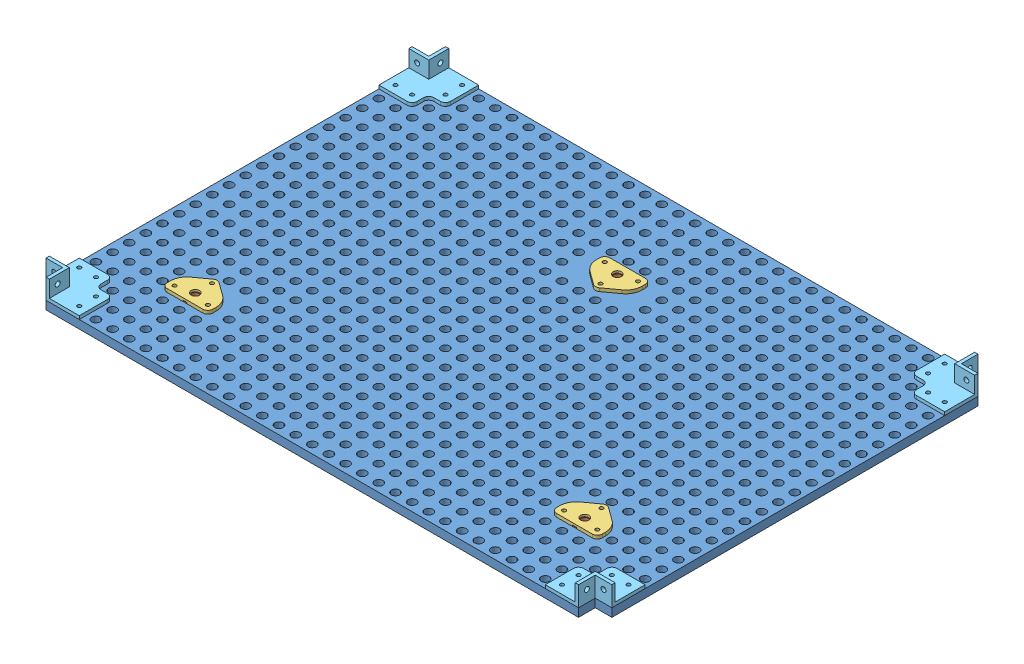
SolidWorks assembly PlateauZ, configuration Défaut. Lengths in mm.
Overall size (680 38 480).
14 component instances, 5 part files, 36 mates.
Components (placement in the parent):
- plaque_repartition_aire_chaud_300x544mm-1: plaque_repartition_aire_chaud_300x544mm [Défaut] at (-104.4522 80.5239 57) size (680 10 480)
- F608ZZ-2: F608ZZ [Défaut] at (-318.4522 85.0239 173.5) x (1 0 0) z (0 1 0) size (25 25 7)
- F608ZZ-3: F608ZZ [Défaut] at (149.5478 85.0239 173.5) x (1 0 0) z (0 1 0) size (25 25 7)
- F608ZZ-4: F608ZZ [Défaut] at (-84.4522 85.0239 -99.5) x (1 0 0) z (0 1 0) size (25 25 7)
- BloqueF608ZZHaut-1: BloqueF608ZZHaut [Défaut] at (122.0829 90.5239 145.9649) x (-0.999999 0 -0.001276) z (0 1 0) size (55 38.58 4)
- BloqueF608ZZHaut-2: BloqueF608ZZHaut [Défaut] at (-345.9522 90.5239 146) x (-1 0 0) z (0 1 0) size (55 38.58 4)
- BloqueF608ZZHaut-3: BloqueF608ZZHaut [Défaut] at (-56.9522 90.5239 -72) x (1 0 0) z (0 1 0) size (55 38.58 4)
- BloqueF608ZZBas-1: BloqueF608ZZBas [Défaut] at (177.0829 80.5239 146.0351) x (0.999999 0 0.001276) z (0 -1 0) size (55 38.58 8.5)
- BloqueF608ZZBas-2: BloqueF608ZZBas [Défaut] at (-290.9522 80.5239 146) x (1 0 0) z (0 -1 0) size (55 38.58 8.5)
- BloqueF608ZZBas-3: BloqueF608ZZBas [Défaut] at (-111.9522 80.5239 -72) x (-1 0 0) z (0 -1 0) size (55 38.58 8.5)
- FixationPlateauZ-1: FixationPlateauZ [Défaut] at (255.5478 90.5239 -193) x (0 0 -1) z (0 1 0) size (60 60 24)
- FixationPlateauZ-2: FixationPlateauZ [Défaut] at (235.5478 90.5239 267) x (1 0 0) z (0 1 0) size (60 60 24)
- FixationPlateauZ-3: FixationPlateauZ [Défaut] at (-424.4522 90.5239 247) x (0 0 1) z (0 1 0) size (60 60 24)
- FixationPlateauZ-4: FixationPlateauZ [Défaut] at (-404.4522 90.5239 -213) x (-1 0 0) z (0 1 0) size (60 60 24)
Mates (geometry in assembly coordinates):
- Coaxiale1: concentric aligned: cylinder of plaque_repartition_aire_chaud_300x544mm-1 through (-318.4522 90.5239 173.5) axis (0 -1 0) radius 11; cylinder of F608ZZ-2 through (-318.4522 90.5239 173.5) axis (0 -1 0) radius 11
- Coaxiale2: concentric aligned: cylinder of plaque_repartition_aire_chaud_300x544mm-1 through (149.5478 90.5239 173.5) axis (0 -1 0) radius 11; cylinder of F608ZZ-3 through (149.5478 90.5239 173.5) axis (0 -1 0) radius 11
- Coaxiale3: concentric aligned: cylinder of plaque_repartition_aire_chaud_300x544mm-1 through (-84.4522 90.5239 -99.5) axis (0 -1 0) radius 11; cylinder of F608ZZ-4 through (-84.4522 90.5239 -99.5) axis (0 -1 0) radius 11
- Coïncidente1: coincident anti-aligned: plane of plaque_repartition_aire_chaud_300x544mm-1 through (-104.4522 90.5239 57) normal (0 1 0); plane of F608ZZ-4 through (-84.4522 90.5239 -99.5) normal (0 -1 0)
- Coïncidente2: coincident anti-aligned: plane of plaque_repartition_aire_chaud_300x544mm-1 through (-104.4522 90.5239 57) normal (0 1 0); plane of F608ZZ-2 through (-318.4522 90.5239 173.5) normal (0 -1 0)
- Coïncidente3: coincident anti-aligned: plane of plaque_repartition_aire_chaud_300x544mm-1 through (-104.4522 90.5239 57) normal (0 1 0); plane of F608ZZ-3 through (149.5478 90.5239 173.5) normal (0 -1 0)
- Coïncidente4: coincident anti-aligned: plane of plaque_repartition_aire_chaud_300x544mm-1 through (-104.4522 90.5239 57) normal (0 1 0); plane of BloqueF608ZZHaut-1 through (122.0829 90.5239 145.9649) normal (0 -1 0)
- Coaxiale4: concentric aligned: cylinder of plaque_repartition_aire_chaud_300x544mm-1 through (149.5733 90.5239 153.5) axis (0 -1 0) radius 2.25; cylinder of BloqueF608ZZHaut-1 through (149.5733 94.5239 153.5) axis (0 -1 0) radius 2.25
- Coaxiale5: concentric aligned: cylinder of F608ZZ-3 through (149.5478 90.5239 173.5) axis (0 -1 0) radius 4; cylinder of BloqueF608ZZHaut-1 through (149.5478 94.5239 173.5) axis (0 -1 0) radius 5
- Coïncidente5: coincident anti-aligned: plane of plaque_repartition_aire_chaud_300x544mm-1 through (-104.4522 90.5239 57) normal (0 1 0); plane of BloqueF608ZZHaut-2 through (-345.9522 90.5239 146) normal (0 -1 0)
- Coaxiale6: concentric aligned: cylinder of F608ZZ-2 through (-318.4522 90.5239 173.5) axis (0 -1 0) radius 4; cylinder of BloqueF608ZZHaut-2 through (-318.4522 94.5239 173.5) axis (0 -1 0) radius 5
- Coaxiale7: concentric aligned: cylinder of plaque_repartition_aire_chaud_300x544mm-1 through (-318.4522 90.5239 153.5) axis (0 -1 0) radius 2.25; cylinder of BloqueF608ZZHaut-2 through (-318.4522 94.5239 153.5) axis (0 -1 0) radius 2.25
- Coïncidente6: coincident anti-aligned: plane of plaque_repartition_aire_chaud_300x544mm-1 through (-104.4522 90.5239 57) normal (0 1 0); plane of BloqueF608ZZHaut-3 through (-56.9522 90.5239 -72) normal (0 -1 0)
- Coaxiale8: concentric aligned: cylinder of F608ZZ-4 through (-84.4522 90.5239 -99.5) axis (0 -1 0) radius 4; cylinder of BloqueF608ZZHaut-3 through (-84.4522 94.5239 -99.5) axis (0 -1 0) radius 5
- Coaxiale12: concentric aligned: cylinder of plaque_repartition_aire_chaud_300x544mm-1 through (-84.4522 90.5239 -79.5) axis (0 -1 0) radius 2.25; cylinder of BloqueF608ZZHaut-3 through (-84.4522 94.5239 -79.5) axis (0 -1 0) radius 2.25
- Coïncidente7: coincident anti-aligned: plane of plaque_repartition_aire_chaud_300x544mm-1 through (-104.4522 80.5239 57) normal (0 -1 0); plane of BloqueF608ZZBas-1 through (177.0829 80.5239 146.0351) normal (0 1 0)
- Coaxiale13: concentric aligned: cylinder of plaque_repartition_aire_chaud_300x544mm-1 through (149.5478 90.5239 173.5) axis (0 -1 0) radius 11; cylinder of BloqueF608ZZBas-1 through (149.5478 85.0239 173.5) axis (0 -1 0) radius 10.75
- Coaxiale14: concentric anti-aligned: cylinder of BloqueF608ZZHaut-1 through (149.5733 94.5239 153.5) axis (0 -1 0) radius 2.25; cylinder of BloqueF608ZZBas-1 through (149.5733 76.5239 153.5) axis (0 1 0) radius 2.25
- Coïncidente8: coincident anti-aligned: plane of plaque_repartition_aire_chaud_300x544mm-1 through (-104.4522 80.5239 57) normal (0 -1 0); plane of BloqueF608ZZBas-2 through (-290.9522 80.5239 146) normal (0 1 0)
- Coaxiale15: concentric aligned: cylinder of plaque_repartition_aire_chaud_300x544mm-1 through (-318.4522 90.5239 173.5) axis (0 -1 0) radius 11; cylinder of BloqueF608ZZBas-2 through (-318.4522 85.0239 173.5) axis (0 -1 0) radius 10.75
- Coaxiale16: concentric anti-aligned: cylinder of BloqueF608ZZHaut-2 through (-318.4522 94.5239 153.5) axis (0 -1 0) radius 2.25; cylinder of BloqueF608ZZBas-2 through (-318.4522 76.5239 153.5) axis (0 1 0) radius 2.25
- Coïncidente9: coincident anti-aligned: plane of plaque_repartition_aire_chaud_300x544mm-1 through (-104.4522 80.5239 57) normal (0 -1 0); plane of BloqueF608ZZBas-3 through (-111.9522 80.5239 -72) normal (0 1 0)
- Coaxiale17: concentric aligned: cylinder of plaque_repartition_aire_chaud_300x544mm-1 through (-84.4522 90.5239 -99.5) axis (0 -1 0) radius 11; cylinder of BloqueF608ZZBas-3 through (-84.4522 85.0239 -99.5) axis (0 -1 0) radius 10.75
- Coaxiale18: concentric anti-aligned: cylinder of BloqueF608ZZHaut-3 through (-84.4522 94.5239 -79.5) axis (0 -1 0) radius 2.25; cylinder of BloqueF608ZZBas-3 through (-84.4522 76.5239 -79.5) axis (0 1 0) radius 2.25
- Coïncidente14: coincident anti-aligned: plane of plaque_repartition_aire_chaud_300x544mm-1 through (-104.4522 90.5239 57) normal (0 1 0); plane of FixationPlateauZ-1 through (255.5478 90.5239 -193) normal (0 -1 0)
- Coïncidente15: coincident aligned: plane of plaque_repartition_aire_chaud_300x544mm-1 through (235.5478 90.5239 -213) normal (1 0 0); plane of FixationPlateauZ-1 through (235.5478 94.5239 -193) normal (1 0 0)
- Coïncidente16: coincident aligned: plane of plaque_repartition_aire_chaud_300x544mm-1 through (235.5478 90.5239 -193) normal (0 0 -1); plane of FixationPlateauZ-1 through (255.5478 94.5239 -193) normal (0 0 -1)
- Coïncidente17: coincident anti-aligned: plane of plaque_repartition_aire_chaud_300x544mm-1 through (-104.4522 90.5239 57) normal (0 1 0); plane of FixationPlateauZ-4 through (-404.4522 90.5239 -213) normal (0 -1 0)
- Coïncidente18: coincident aligned: plane of plaque_repartition_aire_chaud_300x544mm-1 through (-404.4522 90.5239 -213) normal (-1 0 0); plane of FixationPlateauZ-4 through (-404.4522 94.5239 -213) normal (-1 0 0)
- Coïncidente19: coincident aligned: plane of plaque_repartition_aire_chaud_300x544mm-1 through (-424.4522 90.5239 -193) normal (0 0 -1); plane of FixationPlateauZ-4 through (-404.4522 94.5239 -193) normal (0 0 -1)
- Coïncidente20: coincident anti-aligned: plane of plaque_repartition_aire_chaud_300x544mm-1 through (-104.4522 90.5239 57) normal (0 1 0); plane of FixationPlateauZ-3 through (-424.4522 90.5239 247) normal (0 -1 0)
- Coïncidente21: coincident aligned: plane of plaque_repartition_aire_chaud_300x544mm-1 through (-404.4522 90.5239 247) normal (-1 0 0); plane of FixationPlateauZ-3 through (-404.4522 94.5239 247) normal (-1 0 0)
- Coïncidente22: coincident aligned: plane of plaque_repartition_aire_chaud_300x544mm-1 through (-404.4522 90.5239 247) normal (0 0 1); plane of FixationPlateauZ-3 through (-424.4522 94.5239 247) normal (0 0 1)
- Coïncidente23: coincident anti-aligned: plane of plaque_repartition_aire_chaud_300x544mm-1 through (-104.4522 90.5239 57) normal (0 1 0); plane of FixationPlateauZ-2 through (235.5478 90.5239 267) normal (0 -1 0)
- Coïncidente24: coincident aligned: plane of plaque_repartition_aire_chaud_300x544mm-1 through (235.5478 90.5239 247) normal (0 0 1); plane of FixationPlateauZ-2 through (235.5478 94.5239 247) normal (0 0 1)
- Coïncidente25: coincident aligned: plane of plaque_repartition_aire_chaud_300x544mm-1 through (235.5478 90.5239 247) normal (1 0 0); plane of FixationPlateauZ-2 through (235.5478 94.5239 267) normal (1 0 0)
